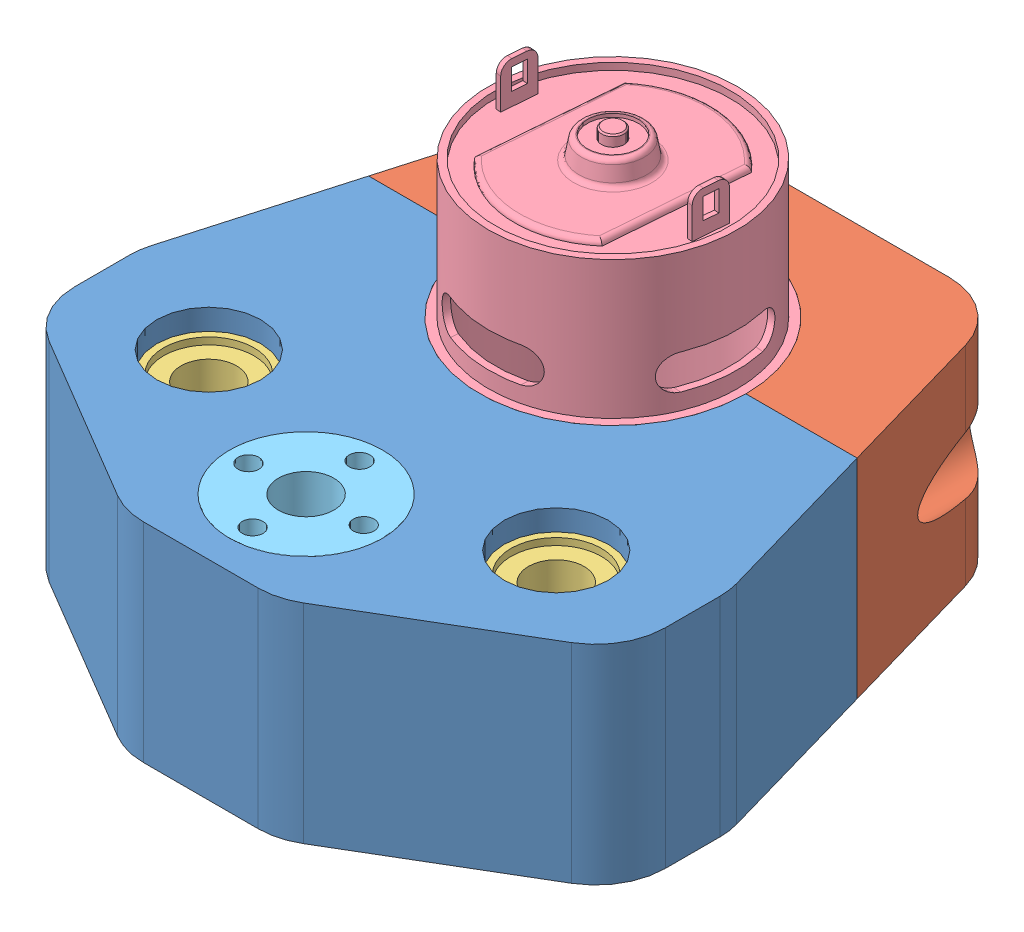
SolidWorks assembly SPINDLE_HOLDER_2, configuration Default. Lengths in mm.
Overall size (85 76.5 88.45).
6 component instances, 5 part files, 11 mates.
Components (placement in the parent):
- PartA-1: PartA [Default] at origin size (85 30 59.3)
- PartB-1: PartB [Default] x (1 0 0) z (0 1 0) size (70.3 29.15 30)
- linear_bearing-1: linear_bearing [Default] at (-25 15 33.15) x (1 0 0) z (0 -1 0) size (15 15 24)
- linear_bearing-2: linear_bearing [Default] at (25 15 33.15) x (1 0 0) z (0 -1 0) size (15 15 24)
- spindle-1: spindle [Default] at (0 -8.2 0) x (0.078415 0 -0.996921) z (0.996921 0 0.078415) size (38.3 76.5 38.3)
- trapezoidal_nut-1: trapezoidal_nut [Default] at (0 30 44.15) x (0.999297 0 -0.037497) z (0 -1 0) size (22 22 15)
Mates (geometry in assembly coordinates):
- Coincident4: coincident anti-aligned: plane of PartA-1 through (0 30 0) normal (0 0 -1); plane of Part5^SPINDLE_HOLDER_2-1 through (0 30 0) normal (0 0 1)
- Coincident5: coincident aligned: plane of PartA-1 through (0 30 0) normal (0 1 0); plane of Part5^SPINDLE_HOLDER_2-1 through (0 30 0) normal (0 1 0)
- Coincident6: coincident aligned: plane of linear_bearing-1 through (-25 26 33.15) normal (0 1 0); plane of linear_bearing-2 through (25 26 33.15) normal (0 1 0)
- Concentric1: concentric anti-aligned: cylinder of PartA-1 through (-25 30 33.15) axis (0 -1 0) radius 7.5; cylinder of linear_bearing-1 through (-25 3 33.15) axis (0 1 0) radius 7.5
- Concentric2: concentric anti-aligned: cylinder of PartA-1 through (25 30 33.15) axis (0 -1 0) radius 7.5; cylinder of linear_bearing-2 through (25 3 33.15) axis (0 1 0) radius 7.5
- Width1: width anti-aligned: plane of linear_bearing-1 through (-25 26 33.15) normal (0 1 0); plane of linear_bearing-1 through (-25 4 33.15) normal (0 -1 0); plane of PartA-1 through (0 0 0) normal (0 -1 0); plane of PartA-1 through (0 30 0) normal (0 1 0)
- Concentric3: concentric aligned: cylinder of PartA-1 through (0 30 0) axis (0 -1 0) radius 19.15; cylinder of spindle-1 through (0 -8.2 0) axis (0 -1 0) radius 19.15
- Concentric4: concentric aligned: cylinder of Part5^SPINDLE_HOLDER_2-1 through (0 30 0) axis (0 -1 0) radius 19.15; cylinder of spindle-1 through (0 -8.2 0) axis (0 -1 0) radius 19.15
- Coincident7: coincident aligned: plane of Part5^SPINDLE_HOLDER_2-1 through (0 30 0) normal (0 1 0); plane of spindle-1 through (4.481 30 -17.33) normal (0 1 0)
- Concentric5: concentric anti-aligned: cylinder of PartA-1 through (0 30 44.15) axis (0 -1 0) radius 5.15; cylinder of trapezoidal_nut-1 through (0 15 44.15) axis (0 1 0) radius 5.15
- Coincident8: coincident anti-aligned: plane of PartA-1 through (0 26 44.15) normal (0 1 0); plane of trapezoidal_nut-1 through (0 26 44.15) normal (0 -1 0)
